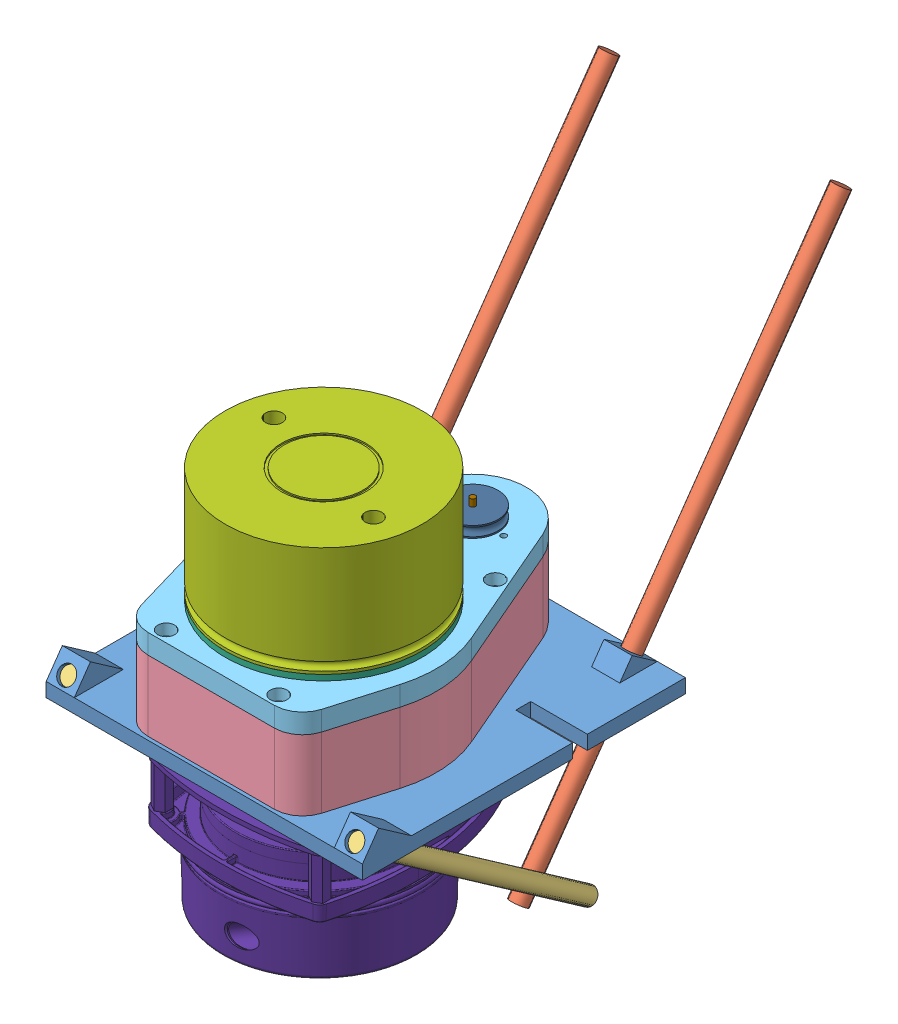
SolidWorks assembly Lidar_support_v1.1, configuration Default. Lengths in mm.
Overall size (112.45 169.25 195.96).
23 component instances, 18 part files, 19 mates.
Components (placement in the parent):
- Pillars-1: Pillars [Default] at (-57.4546 169.2541 -22.7568) (suppressed, hidden)
- Tray-1: Tray [Default] at (32.812 36.0483 54.9073) size (112.45 13.19 114.82)
- Rod_large-1: Rod_large [Default] at (-42.4546 17.6941 9.3986) x (1 0 0) z (0 0.573576 0.819152) size (6 200 6)
- Rod_large-2: Rod_large [Default] at (40 17.6941 9.3986) x (1 0 0) z (0 0.573576 0.819152) size (6 200 6)
- Rod_small-1: Rod_small [Default] at (-52.4546 75.0283 76.4611) x (-1 0 0) z (0 -0.819152 0.573576) size (6 100 6)
- Rod_small-2: Rod_small [Default] at (50 75.0283 76.4611) x (-1 0 0) z (0 -0.819152 0.573576) size (6 100 6)
- LidarBeta-1: LidarBeta [Default] at (0 60.427 38.6055) x (-1 0 0) z (0 0 -1) size (85.95 74.01 114.97)
  - Cover_base-1: Cover_base [Default] at origin size (80 25 112)
  - Cover_top-1: Cover_top [Default] at origin size (80 8 112)
  - Head_base-1: Head_base [Default] at (0 37.0834 0) x (-0.258111 0 0.966115) z (-0.966115 0 -0.258111) size (70 58 70)
  - Head_top-1: Head_top [Default] at (0 15.2712 0) x (0.966115 0 0.258111) z (-0.258111 0 0.966115) size (70 39 70)
  - 6810-1: 6810 [Default] at (0 40.5782 0) x (0 1 0) z (0.911895 0 -0.410424) size (7.01 65 65)
  - RF-530-1: RF-530 [Default] at (0 22.073 53) size (33 31.5 33)
  - Pulley-1: Pulley [Default] at (0 -2.4896 0) size (18 4 18)
  - Slipring_v1.1-1: Slipring_v1.1 [Default] at (0 46.0834 0) x (-0.672958 0 -0.739681) z (-0.739681 0 0.672958) size (22 17 22)
  - Lidar_PCB-1: Lidar_PCB [Default] at (0 14.073 0) size (64 7.6 60)
  - Lidar_Lite_V2-1: Lidar_Lite_V2 [Default] at (-19.3223 65.0834 -5.1622) x (0.258111 0 -0.966115) z (0.966115 0 0.258111) size (48 35.4 39.5)
    - Garmin_Lidar_Lite_3.step-1: Garmin_Lidar_Lite_3.step [Default] at origin size (48 35.4 39.5)
      - Garmin_Lidar_Lite_31.step-1: Garmin_Lidar_Lite_31.step [Default] at origin size (48 35.4 5)
      - Garmin_Lidar_Lite_32.step-1: Garmin_Lidar_Lite_32.step [Default] at origin size (48 20 37)
      - Garmin_Lidar_Lite_33.step-1: Garmin_Lidar_Lite_33.step [Default] at origin size (12.5 4.5 2)
      - Garmin_Lidar_Lite_34.step-1: Garmin_Lidar_Lite_34.step [Default] at origin size (10.35 3.3 4.35)
- RPLidar-1: RPLidar [Default] at (132.9176 787.1923 -50.5207) x (0 0 -1) z (-1 0 0) size (116.38 53.5 95.72)
Mates (geometry in assembly coordinates):
- Coincident5: coincident: plane of assembly through (0 0 0) normal (0 1 0); plane of Pillars-1 through (-37.4546 0 4.5232) normal (0 -1 0); plane of assembly
- Coincident7: coincident: plane of assembly; plane of assembly; plane of Rod_large-1 through (-42.4546 181.5245 -105.3167) normal (0 0.819152 -0.573576); plane of Rod_large-2 through (40 181.5245 -105.3167) normal (0 0.819152 -0.573576)
- Coincident10: coincident: plane of assembly; plane of assembly; plane of Rod_large-1 through (-42.4546 17.6941 9.3986) normal (0 0.573576 0.819152); plane of Rod_large-2 through (40 17.6941 9.3986) normal (0 0.573576 0.819152)
- Coincident11: coincident: plane of assembly; plane of assembly; plane of Rod_small-1 through (-52.4546 17.6707 -5.4541) normal (0 -0.573576 -0.819152); plane of Rod_small-2 through (50 17.6707 -5.4541) normal (0 -0.573576 -0.819152)
- Coincident12: coincident: plane of assembly; plane of assembly; plane of Rod_small-1 through (-52.4546 75.0283 76.4611) normal (0 -0.819152 0.573576); plane of Rod_small-2 through (50 75.0283 76.4611) normal (0 -0.819152 0.573576)
- Tangent1: tangent: plane of assembly; plane of Tray-1 through (32.812 67.5 54.9073) normal (0 -1 0); face of RPLidar-1
- Coincident16: coincident: plane of Tray-1 through (32.812 72.5 54.9073) normal (0 1 0); plane of ? through (22.5 72.5 68.6055) normal (0 -1 0)
- Coincident17: coincident: plane of ? through (0 60.427 38.6055) normal (-1 0 0); plane of assembly through (0 0 0) normal (1 0 0)
- Coincident18: coincident: plane of assembly through (0 0 0) normal (1 0 0); plane of RPLidar-1 through (0 787.1923 -50.5207) normal (-1 0 0); plane of assembly
- Concentric6: concentric: cylinder of assembly; cylinder of assembly; cylinder of Pillars-1 through (-42.4546 137.2495 -74.315) axis (0 -0.819152 0.573576) radius 3.1; cylinder of Rod_large-1 through (-42.4546 181.5245 -105.3167) axis (0 -0.819152 0.573576) radius 3
- Concentric8: concentric: cylinder of assembly; cylinder of assembly; cylinder of Pillars-1 through (-52.4546 76.2703 78.2348) axis (0 -0.573576 -0.819152) radius 3.1; cylinder of Rod_small-1 through (-52.4546 17.6707 -5.4541) axis (0 0.573576 0.819152) radius 3
- Distance9: distance = 0.15 mm: plane of assembly; plane of assembly; plane of Pillars-1 through (-37.4546 140 4.5232) normal (0 0 1); plane of Tray-1 through (32.812 67.5 4.6732) normal (0 0 -1)
- Distance10: distance = 0.15 mm: plane of assembly; plane of assembly; plane of Pillars-1 through (-37.4546 169.2541 -22.7568) normal (1 0 0); plane of Tray-1 through (-37.3046 67.5 54.9073) normal (-1 0 0)
- Distance11: distance = 0.8246 mm: plane of assembly; plane of assembly; plane of Pillars-1 through (-47.4546 127.9873 -81.692) normal (0 -0.573576 -0.819152); plane of Rod_small-1 through (-52.4546 17.6707 -5.4541) normal (0 -0.573576 -0.819152)
- Distance12: distance = 1 mm: plane of assembly; plane of assembly; plane of Pillars-1 through (-47.4546 53.2669 58.4584) normal (0 -0.819152 0.573576); plane of Rod_large-1 through (-42.4546 17.6941 9.3986) normal (0 -0.819152 0.573576)
- Concentric9: concentric: cylinder of assembly; cylinder of assembly; cylinder of Tray-1 through (50 20.182 -1.8676) axis (0 0.573576 0.819152) radius 3.1; cylinder of Rod_small-2 through (50 17.6707 -5.4541) axis (0 0.573576 0.819152) radius 3
- Coincident25: coincident: plane of assembly; plane of assembly; plane of Rod_small-1 through (-52.4546 75.0283 76.4611) normal (0 0.573576 0.819152); plane of Rod_small-2 through (50 75.0283 76.4611) normal (0 0.573576 0.819152)
- Concentric10: concentric: cylinder of assembly; cylinder of assembly; cylinder of Tray-1 through (40 15.5933 10.8695) axis (0 0.819152 -0.573576) radius 3.1; cylinder of Rod_large-2 through (40 181.5245 -105.3167) axis (0 -0.819152 0.573576) radius 3
- Coincident26: coincident: plane of assembly; plane of assembly; plane of Rod_large-1 through (-42.4546 181.5245 -105.3167) normal (0 0.819152 -0.573576); plane of Rod_large-2 through (40 181.5245 -105.3167) normal (0 0.819152 -0.573576)
